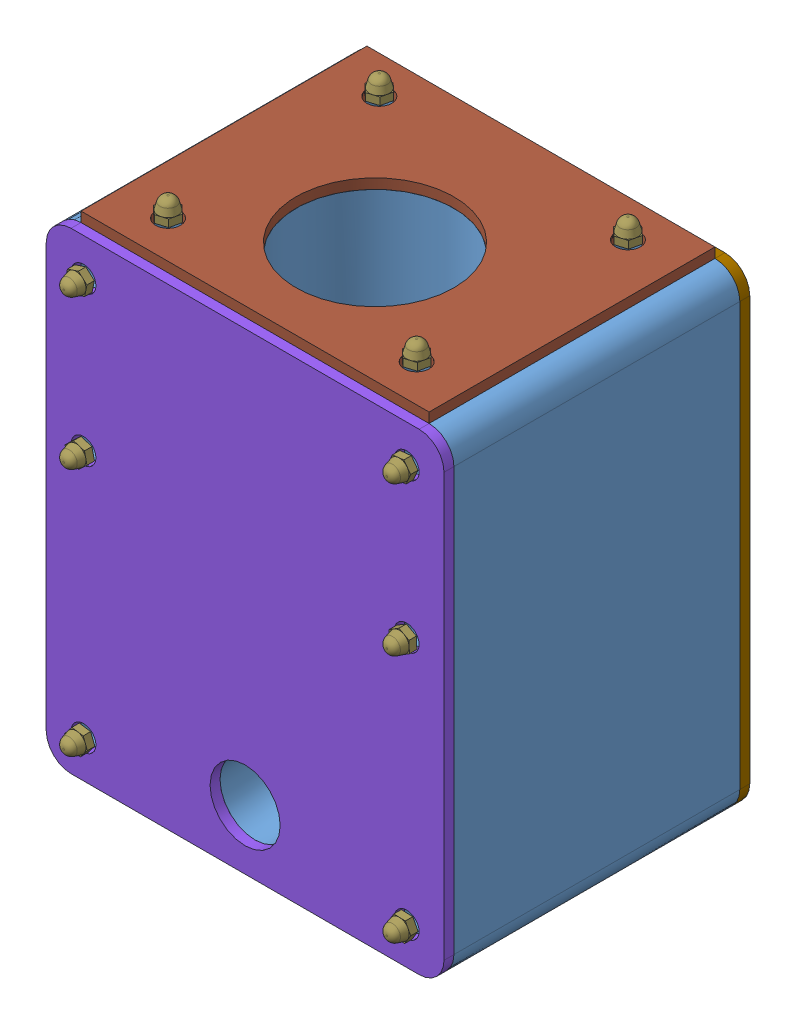
SolidWorks assembly pompa son hali, configuration Varsayılan. Lengths in mm.
Overall size (160 202 157).
25 component instances, 12 part files, 54 mates.
Components (placement in the parent):
- kestamid gövde 3-1: kestamid gövde 3 [Varsayılan] at (227.9138 5.4302 190) size (160 190 115.04)
- keçe-1: keçe [Ø90x140x12] at (38.1304 -12.1784 181.239) x (0 0 1) z (0.745072 0.666984 0) size (1.6 18.67 18.67)
- keçe-2: keçe [Ø90x140x12] at (-13.8696 -12.1784 181.239) x (0 0 1) z (0.244046 -0.969764 0) size (1.6 18.67 18.67)
- Rulman-1: Rulman [6000-26x10x8mm] at (-13.8696 -12.1784 167.2) x (0 0 -1) z (1 0 0) size (9.6 31.2 31.2)
- Rulman-2: Rulman [6000-26x10x8mm] at (38.1304 -12.1784 167.2) x (0 0 1) z (-1 0 0) size (9.6 31.2 31.2)
- keçe-3: keçe [Ø90x140x12] at (-13.8696 -12.1784 185.161) x (0 0 -1) z (0.999964 -0.008516 0) size (1.6 18.67 18.67)
- keçe-4: keçe [Ø90x140x12] at (38.1304 -12.1784 185.161) x (0 0 -1) z (0.999392 -0.034862 0) size (1.6 18.67 18.67)
- 12mm mil 2 motor-1: 12mm mil 2 motor [Varsayılan] at (-13.8021 -11.9837 225) x (-0.059417 -0.998233 0) z (0 0 1) size (13.56 13.17 145)
- 12mm mil 1-1: 12mm mil 1 [Varsayılan] at (37.7883 -11.4885 217.5) x (0.895916 0.444224 0) z (0 0 1) size (12 12 115)
- dişli 3 boşta-1: dişli 3 boşta [Varsayılan] at (38.1304 -12.1784 225) x (-0.492949 0.870058 0) z (0 0 1) size (61 61 70)
- dişli 3 motor-1: dişli 3 motor [Varsayılan] at (-13.2762 -12.09 225) x (-0.125676 -0.992071 0) z (0 0 1) size (61 61 70)
- paslanmaz ön 3-1: paslanmaz ön 3 [Varsayılan] at (12.0045 0.2021 275) size (160 190 4)
- paslanmaz arka 3-1: paslanmaz arka 3 [Varsayılan] at (12.0045 0.2021 156) size (160 190 4)
- kestamid kapak-1: kestamid kapak [Varsayılan] at (12.0045 0.2021 271) size (136.8 84.8 15.05)
- paslanmaz üst-1: paslanmaz üst [Varsayılan] at (12.263 98.8216 217.381) x (-1 0 0) z (0 -1 0) size (140 115 4)
- somun-1: somun [Varsayılan] at (-52.8696 79.8216 219) x (-0.485551 -0.874208 0) z (0 0 1) size (8.82 9.01 8)
- somun-2: somun [Varsayılan] at (-52.8696 19.8216 219) x (0.825026 -0.565095 0) z (0 0 1) size (8.82 9.01 8)
- somun-3: somun [Varsayılan] at (-52.8696 -80.1784 219) x (0.900566 -0.43472 0) z (0 0 1) size (8.82 9.01 8)
- somun-4: somun [Varsayılan] at (77.1304 -80.1784 219) x (0.944609 -0.328198 0) z (0 0 1) size (8.82 9.01 8)
- somun-5: somun [Varsayılan] at (77.1304 19.8216 219) x (0.968756 0.248015 0) z (0 0 1) size (8.82 9.01 8)
- somun-6: somun [Varsayılan] at (77.1304 79.8216 219) x (0.982122 -0.188244 0) z (0 0 1) size (8.82 9.01 8)
- somun-7: somun [Varsayılan] at (-37.8696 38.8216 260) x (1 0 0) z (0 1 0) size (8.82 9.01 8)
- somun-8: somun [Varsayılan] at (-37.8696 38.8216 175) x (1 0 0) z (0 1 0) size (8.82 9.01 8)
- somun-9: somun [Varsayılan] at (62.1304 38.8216 260) x (1 0 0) z (0 1 0) size (8.82 9.01 8)
- somun-10: somun [Varsayılan] at (62.1304 38.8216 175) x (1 0 0) z (0 1 0) size (8.82 9.01 8)
Mates (geometry in assembly coordinates):
- Eş Merkezli1: concentric anti-aligned: circle of kestamid gövde 3-1; circle of keçe-1
- Çakışık1: coincident anti-aligned: plane of kestamid gövde 3-1 through (38.1304 -12.1784 178) normal (0 0 -1); plane of keçe-1 through (44.3358 -19.1103 178) normal (0 0 1)
- Eş Merkezli2: concentric anti-aligned: circle of kestamid gövde 3-1; circle of keçe-2
- Çakışık5: coincident anti-aligned: plane of kestamid gövde 3-1 through (-13.8696 -12.1784 178) normal (0 0 -1); plane of keçe-2 through (-22.892 -14.4489 178) normal (0 0 1)
- Çakışık6: coincident anti-aligned: plane of kestamid gövde 3-1 through (38.1304 -12.1784 172) normal (0 0 -1); plane of Rulman-2 through (38.1304 3.0616 172) normal (0 0 1)
- Eş Merkezli3: concentric anti-aligned: circle of kestamid gövde 3-1; circle of Rulman-2
- Çakışık7: coincident anti-aligned: plane of kestamid gövde 3-1 through (-13.8696 -12.1784 172) normal (0 0 -1); plane of Rulman-1 through (-13.8696 0.5416 172) normal (0 0 1)
- Eş Merkezli4: concentric aligned: circle of kestamid gövde 3-1; circle of Rulman-1
- Eş Merkezli5: concentric anti-aligned: circle of kestamid gövde 3-1; circle of keçe-3
- Eş Merkezli6: concentric anti-aligned: circle of kestamid gövde 3-1; circle of keçe-4
- Çakışık10: coincident aligned: plane of kestamid gövde 3-1 through (-57.8696 -85.1784 190) normal (0 0 1); plane of keçe-3 through (-13.7924 -3.1121 190) normal (0 0 1)
- Çakışık11: coincident aligned: plane of kestamid gövde 3-1 through (-57.8696 -85.1784 190) normal (0 0 1); plane of keçe-4 through (38.4465 -3.1172 190) normal (0 0 1)
- Eş Merkezli8: concentric anti-aligned: circle of keçe-3; circle of 12mm mil 2 motor-1
- Çakışık14: coincident aligned: plane of kestamid gövde 3-1 through (82.1304 84.8216 275) normal (0 0 1); plane of 12mm mil 2 motor-1 through (-13.8696 -12.1784 275) normal (0 0 1)
- Eş Merkezli9: concentric aligned: circle of kestamid gövde 3-1; circle of 12mm mil 1-1
- Çakışık15: coincident aligned: plane of kestamid gövde 3-1 through (82.1304 84.8216 275) normal (0 0 1); plane of 12mm mil 1-1 through (38.1304 -12.1784 275) normal (0 0 1)
- Eş Merkezli10: concentric aligned: circle of 12mm mil 1-1; circle of dişli 3 boşta-1
- Çakışık17: coincident aligned: plane of kestamid gövde 3-1 through (227.9138 5.4302 260) normal (0 0 1); plane of dişli 3 boşta-1 through (38.1304 -12.1784 260) normal (0 0 1)
- Çakışık18: coincident anti-aligned: plane of kestamid gövde 3-1 through (-57.8696 -85.1784 190) normal (0 0 1); plane of dişli 3 motor-1 through (-13.2762 -12.09 190) normal (0 0 -1)
- Çakışık19: coincident: plane of 12mm mil 2 motor-1 through (-19.2937 -16.4888 260) normal (-0.366934 -0.930247 0); line of dişli 3 motor-1 through (-18.9714 -16.6159 260) axis (0.930247 -0.366934 0)
- Çakışık20: coincident anti-aligned: plane of 12mm mil 2 motor-1 through (-14.8905 -5.3258 260) normal (-0.622151 0.782898 0); plane of dişli 3 motor-1 through (-14.3481 -4.8948 170.1267) normal (0.622151 -0.782898 0)
- GearMate2: gear = 52 : 52 mm: circle of dişli 3 motor-1; circle of dişli 3 boşta-1
- Çakışık24: coincident aligned: plane of kestamid gövde 3-1 through (-67.8696 94.8216 260) normal (-1 0 0); plane of paslanmaz arka 3-1 through (-67.8696 84.8216 160) normal (-1 0 0)
- Çakışık25: coincident anti-aligned: plane of kestamid gövde 3-1 through (-57.8696 -85.1784 160) normal (0 0 -1); plane of paslanmaz arka 3-1 through (82.1304 84.8216 160) normal (0 0 1)
- Çakışık26: coincident aligned: plane of kestamid gövde 3-1 through (-67.8696 94.8216 260) normal (0 1 0); plane of paslanmaz arka 3-1 through (82.1304 94.8216 160) normal (0 1 0)
- Eş Merkezli11: concentric anti-aligned: circle of 12mm mil 1-1; circle of kestamid kapak-1
- Eş Merkezli12: concentric anti-aligned: circle of 12mm mil 2 motor-1; circle of kestamid kapak-1
- Çakışık27: coincident anti-aligned: plane of kestamid gövde 3-1 through (227.9138 5.4302 260) normal (0 0 1); plane of kestamid kapak-1 through (-13.8696 -12.1784 260) normal (0 0 -1)
- Çakışık28: coincident aligned: plane of kestamid gövde 3-1 through (-67.8696 94.8216 260) normal (-1 0 0); plane of paslanmaz ön 3-1 through (-67.8696 84.8216 279) normal (-1 0 0)
- Çakışık29: coincident aligned: plane of kestamid gövde 3-1 through (-67.8696 94.8216 260) normal (0 1 0); plane of paslanmaz ön 3-1 through (82.1304 94.8216 279) normal (0 1 0)
- Çakışık30: coincident anti-aligned: plane of kestamid gövde 3-1 through (82.1304 84.8216 275) normal (0 0 1); plane of paslanmaz ön 3-1 through (82.1304 84.8216 275) normal (0 0 -1)
- Çakışık31: coincident anti-aligned: plane of kestamid gövde 3-1 through (-67.8696 94.8216 260) normal (0 1 0); plane of paslanmaz üst-1 through (12.263 94.8216 217.381) normal (0 -1 0)
- Eş Merkezli13: concentric anti-aligned: circle of kestamid gövde 3-1; circle of paslanmaz üst-1
- Eş Merkezli14: concentric aligned: circle of kestamid gövde 3-1; circle of paslanmaz üst-1
- Eş Merkezli15: concentric aligned: circle of kestamid gövde 3-1; circle of somun-1
- Çakışık33: coincident anti-aligned: plane of paslanmaz ön 3-1 through (82.1304 84.8216 279) normal (0 0 1); plane of somun-1 through (-52.8696 79.8216 279) normal (0 0 -1)
- Eş Merkezli16: concentric anti-aligned: circle of kestamid gövde 3-1; circle of somun-6
- Çakışık34: coincident anti-aligned: plane of paslanmaz ön 3-1 through (82.1304 84.8216 279) normal (0 0 1); plane of somun-6 through (77.1304 79.8216 279) normal (0 0 -1)
- Eş Merkezli17: concentric: circle of kestamid gövde 3-1; circle of somun-2
- Çakışık35: coincident anti-aligned: plane of paslanmaz ön 3-1 through (82.1304 84.8216 279) normal (0 0 1); plane of somun-2 through (-52.8696 19.8216 279) normal (0 0 -1)
- Eş Merkezli18: concentric: circle of kestamid gövde 3-1; circle of somun-5
- Çakışık36: coincident anti-aligned: plane of paslanmaz ön 3-1 through (82.1304 84.8216 279) normal (0 0 1); plane of somun-5 through (77.1304 19.8216 279) normal (0 0 -1)
- Eş Merkezli19: concentric: circle of kestamid gövde 3-1; circle of somun-3
- Çakışık37: coincident anti-aligned: plane of paslanmaz ön 3-1 through (82.1304 84.8216 279) normal (0 0 1); plane of somun-3 through (-52.8696 -80.1784 279) normal (0 0 -1)
- Eş Merkezli20: concentric: circle of kestamid gövde 3-1; circle of somun-4
- Çakışık38: coincident anti-aligned: plane of paslanmaz ön 3-1 through (82.1304 84.8216 279) normal (0 0 1); plane of somun-4 through (77.1304 -80.1784 279) normal (0 0 -1)
- Eş Merkezli21: concentric: circle of paslanmaz üst-1; circle of somun-8
- Çakışık39: coincident anti-aligned: plane of paslanmaz üst-1 through (12.263 98.8216 217.381) normal (0 1 0); plane of somun-8 through (-37.8696 98.8216 175) normal (0 -1 0)
- Eş Merkezli22: concentric: circle of paslanmaz üst-1; circle of somun-7
- Çakışık40: coincident anti-aligned: plane of paslanmaz üst-1 through (12.263 98.8216 217.381) normal (0 1 0); plane of somun-7 through (-37.8696 98.8216 260) normal (0 -1 0)
- Eş Merkezli23: concentric: circle of paslanmaz üst-1; circle of somun-10
- Çakışık41: coincident anti-aligned: plane of paslanmaz üst-1 through (12.263 98.8216 217.381) normal (0 1 0); plane of somun-10 through (62.1304 98.8216 175) normal (0 -1 0)
- Eş Merkezli24: concentric: circle of paslanmaz üst-1; circle of somun-9
- Çakışık42: coincident anti-aligned: plane of paslanmaz üst-1 through (12.263 98.8216 217.381) normal (0 1 0); plane of somun-9 through (62.1304 98.8216 260) normal (0 -1 0)
